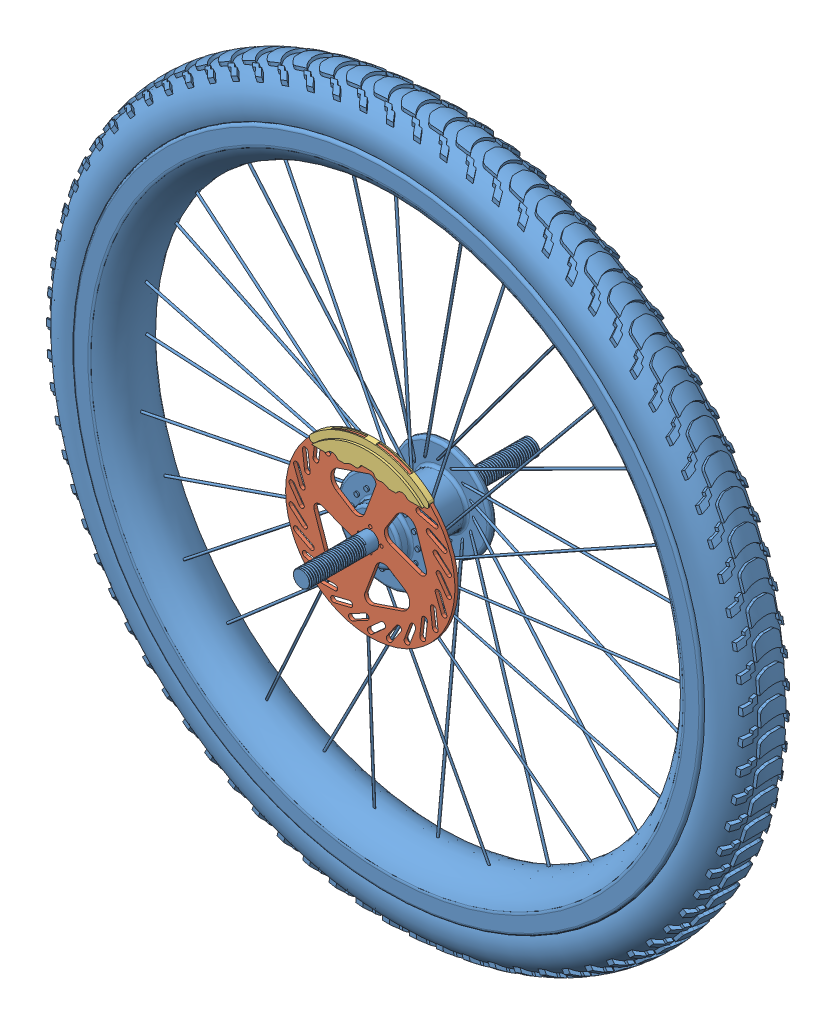
SolidWorks assembly wheal_break assembly, configuration Default. Lengths in mm.
Overall size (635.87 635.93 205.05).
4 component instances, 3 part files, 3 mates.
Components (placement in the parent):
- _edited-1: _edited [Default] at (-24.9726 1.9472 38.4573) size (635.87 635.93 205.05)
- BREAK_assembly-1: BREAK_assembly [Default] at (55.7193 -7.9409 15.5251) size (150 151 7)
  - brake-1: brake [Default] at (-80.6919 9.888 34.3622) size (150 150 3)
  - BreaK_TOP-1: BreaK_TOP [Default] at (-80.6919 9.888 35.8622) size (105.33 26 7)
Mates (geometry in assembly coordinates):
- Concentric1: concentric aligned: cylinder of _edited-1 through (-24.9726 1.9472 113.3873) axis (0 0 1) radius 7.62; circle of BREAK_assembly-1/brake-1
- Parallel1: parallel aligned: plane of _edited-1 through (-24.9726 1.9472 38.4573) normal (1 0 0); plane of BREAK_assembly-1 through (55.7193 -7.9409 15.5251) normal (1 0 0)
- Coincident2: coincident anti-aligned: plane of _edited-1 through (-24.9726 9.5672 49.8873) normal (0 0 1); plane of BREAK_assembly-1/brake-1 through (-24.9726 1.9472 49.8873) normal (0 0 -1)
